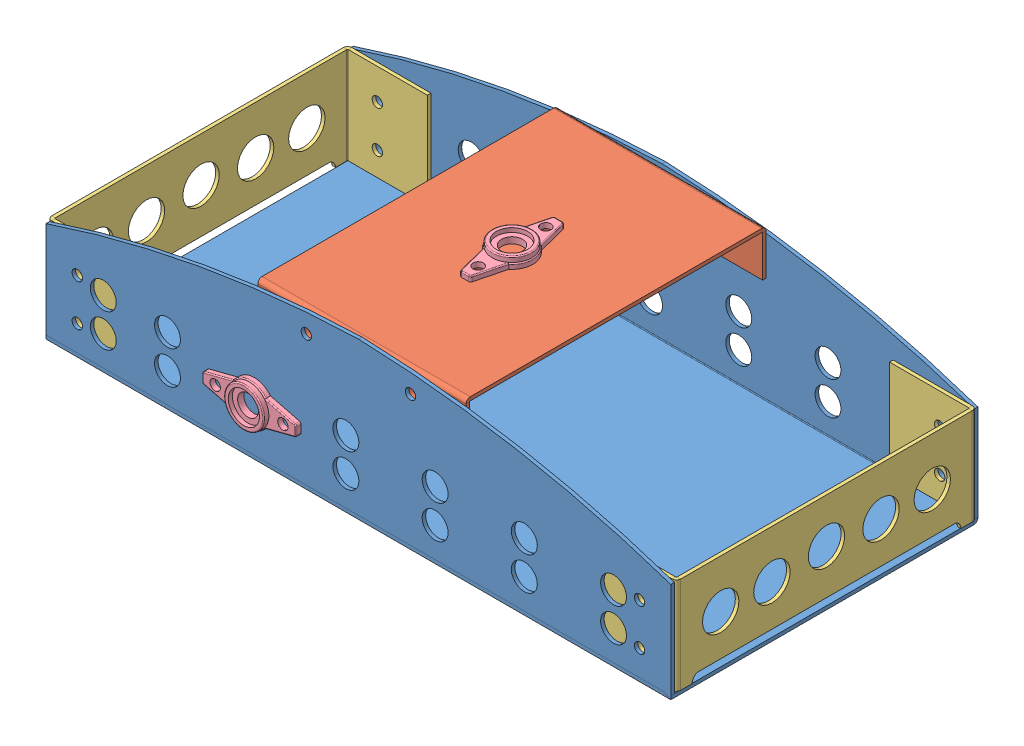
SolidWorks assembly Box Asm, configuration Default. Lengths in mm.
Overall size (604 158.3 315).
7 component instances, 4 part files, 8 mates.
Components (placement in the parent):
- Box base-1: Box base [Default] at (475.9416 232.8332 420.8595) size (600 150 295)
- Box head-1: Box head [Default] at (275.9416 324.7821 709.0595) x (0 0 1) z (0 1 0) size (288.2 200 43.4)
- Box sides-1: Box sides [Default] at (-122.6584 274.1861 420.8595) x (0 0 -1) z (1 0 0) size (288.2 92.6 80)
- Box sides-2: Box sides [Default] at (474.5416 274.1861 709.0595) x (0 0 1) z (-1 0 0) size (288.2 92.6 80)
- Bearing connector-1: Bearing connector [Default] at (175.9416 324.7821 564.9595) x (0 0 1) z (0 1 0) size (90 40 10)
- Bearing connector-2: Bearing connector [Default] at (75.9416 224.4861 417.4595) x (-1 0 0) z (0 0 -1) size (90 40 10)
- Bearing connector-3: Bearing connector [Default] at (75.9416 224.4861 712.4595) size (90 40 10)
Mates (geometry in assembly coordinates):
- Coincident1: coincident anti-aligned: circle of Box base-1; circle of Box head-1
- Coincident2: coincident anti-aligned: circle of Box base-1; circle of Box head-1
- Coincident5: coincident anti-aligned: circle of Box base-1; circle of Box sides-1
- Coincident6: coincident anti-aligned: circle of Box base-1; circle of Box sides-1
- Coincident7: coincident anti-aligned: circle of Box head-1; circle of Bearing connector-1
- Concentric1: concentric anti-aligned: cylinder of Box head-1 through (175.9416 321.3821 597.4595) axis (0 1 0) radius 5; cylinder of Bearing connector-1 through (175.9416 329.7821 597.4595) axis (0 -1 0) radius 5
- Coincident8: coincident anti-aligned: circle of Box base-1; circle of Bearing connector-2
- Concentric2: concentric aligned: cylinder of Box base-1 through (108.4416 224.4861 417.4595) axis (0 0 1) radius 5; cylinder of Bearing connector-2 through (108.4416 224.4861 412.4595) axis (0 0 1) radius 5
